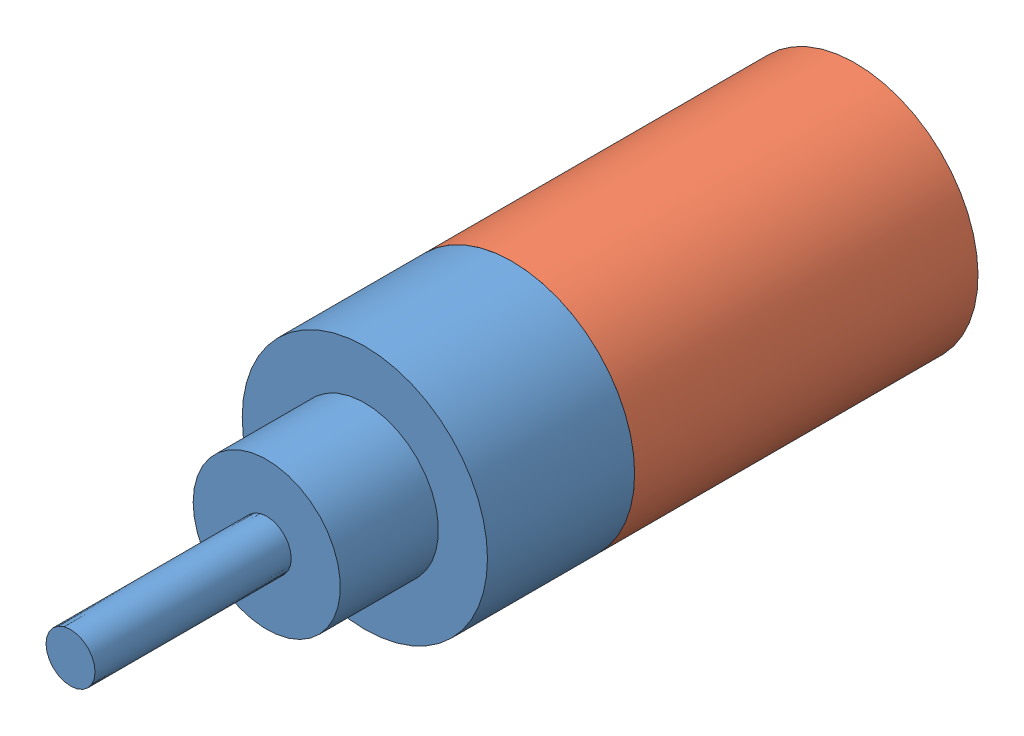
SolidWorks assembly Yucra_Fabrizio_E03, configuration Predeterminado. Lengths in mm.
Overall size (123.65 123.65 320).
2 component instances, 2 part files, 2 mates.
Components (placement in the parent):
- Yucra_Fabrizio_P55A-1: Yucra_Fabrizio_P55A [Predeterminado] at (-14.1984 3.7908 300) size (100 100 300)
- Yucra_Fabrizio_P55B-2: Yucra_Fabrizio_P55B [Predeterminado] at (-14.1984 3.7908 130) x (-0.275042 0.961432 0) z (0 0 -1) size (100 100 140)
Mates (geometry in assembly coordinates):
- Concéntrica1: concentric aligned: cylinder of Yucra_Fabrizio_P55A-1 through (-14.1984 3.7908 150) axis (0 0 -1) radius 10; cylinder of Yucra_Fabrizio_P55B-2 through (-14.1984 3.7908 130) axis (0 0 -1) radius 10
- Coincidente1: coincident anti-aligned: plane of Yucra_Fabrizio_P55A-1 through (-14.1984 53.7908 270) normal (0 0 -1); plane of Yucra_Fabrizio_P55B-2 through (33.8732 17.5429 270) normal (0 0 1)
